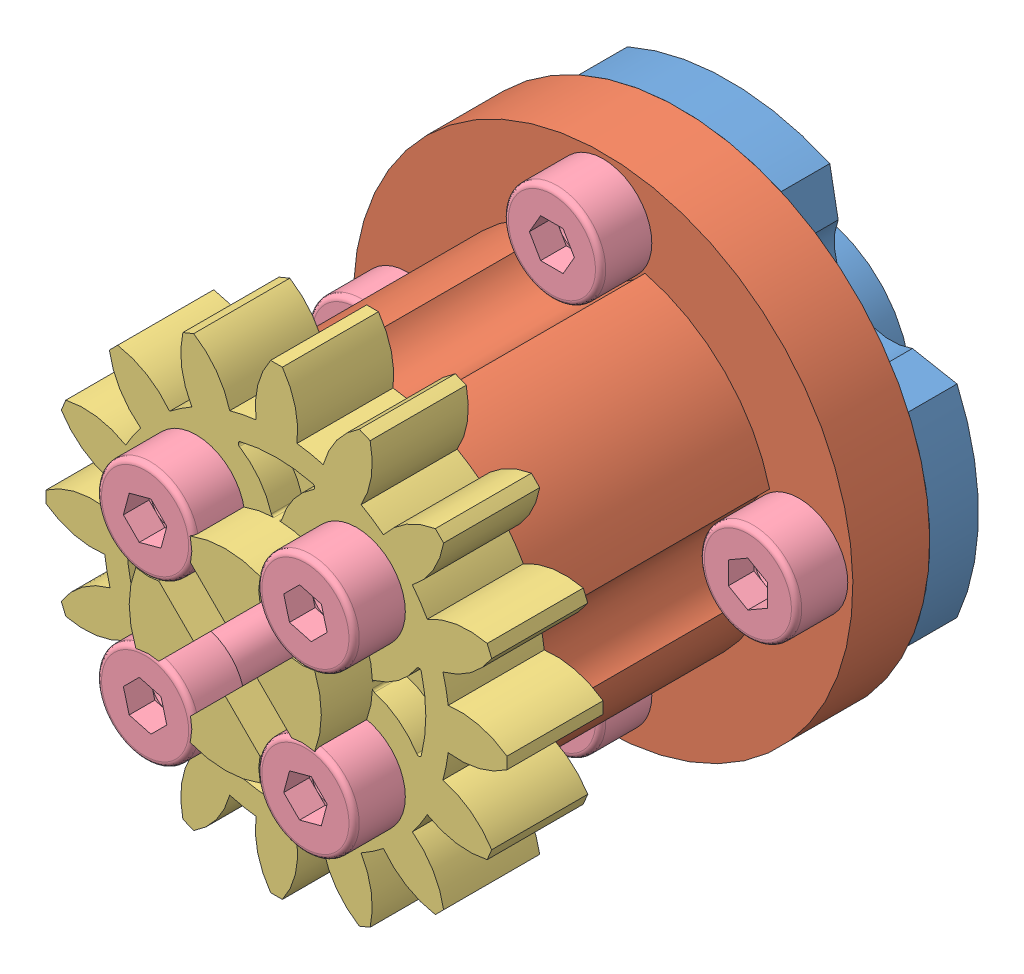
SolidWorks assembly Adapter-Servo-Zahnrad-16Z, configuration Standard. Lengths in mm.
Overall size (27.58 27.58 22.65).
11 component instances, 4 part files, 15 mates.
Components (placement in the parent):
- Servo-Horn-4er-modifiziert-1: Servo-Horn-4er-modifiziert [Standard] at origin size (19.5 19.5 5.7)
- Adapter-Servo-Zahnrad-16Z-1: Adapter-Servo-Zahnrad-16Z [Standard] at (0 0 4.8) x (-0.707107 0.707107 0) z (0 0 1) size (19.5 19.5 12)
- Lego Zahnrad 16Z-1: Lego Zahnrad 16Z [Standard] at (0 0 15.675) x (-0.707107 0.707107 0) z (0 0 1) size (18 18 7.75)
- DIN 912 M2 x 6 --- 6N-1: DIN 912 M2 x 6 --- 6N [DIN 912 M2 x 6 --- 6N] at (-3.1289 -3.1289 19.55) x (0 0 -1) z (-0.707107 0.707107 0) size (8 3.8 3.8)
- DIN 912 M2 x 6 --- 6N-2: DIN 912 M2 x 6 --- 6N [DIN 912 M2 x 6 --- 6N] at (-3.1289 3.1289 19.55) x (0 0 -1) z (0.707107 0.707107 0) size (8 3.8 3.8)
- DIN 912 M2 x 6 --- 6N-3: DIN 912 M2 x 6 --- 6N [DIN 912 M2 x 6 --- 6N] at (3.1289 3.1289 19.55) x (0 0 -1) z (0.707107 -0.707107 0) size (8 3.8 3.8)
- DIN 912 M2 x 6 --- 6N-4: DIN 912 M2 x 6 --- 6N [DIN 912 M2 x 6 --- 6N] at (3.1289 -3.1289 19.55) x (0 0 -1) z (-0.707107 -0.707107 0) size (8 3.8 3.8)
- DIN 912 M2 x 6 --- 6N-5: DIN 912 M2 x 6 --- 6N [DIN 912 M2 x 6 --- 6N] at (0 7.65 6.8) x (0 0 -1) z (0 1 0) size (8 3.8 3.8)
- DIN 912 M2 x 6 --- 6N-6: DIN 912 M2 x 6 --- 6N [DIN 912 M2 x 6 --- 6N] at (7.65 0 6.8) x (0 0 -1) z (1 0 0) size (8 3.8 3.8)
- DIN 912 M2 x 6 --- 6N-7: DIN 912 M2 x 6 --- 6N [DIN 912 M2 x 6 --- 6N] at (0 -7.65 6.8) x (0 0 -1) z (0 -1 0) size (8 3.8 3.8)
- DIN 912 M2 x 6 --- 6N-8: DIN 912 M2 x 6 --- 6N [DIN 912 M2 x 6 --- 6N] at (-7.65 0 6.8) x (0 0 -1) z (-1 0 0) size (8 3.8 3.8)
Mates (geometry in assembly coordinates):
- Konzentrisch1: concentric aligned: cylinder of Adapter-Servo-Zahnrad-16Z-1 through (0 0 13.8) axis (0 0 -1) radius 3.75; cylinder of Lego Zahnrad 16Z-1 through (0 0 19.55) axis (0 0 -1) radius 3.75
- Deckungsgleich5: coincident anti-aligned: plane of Adapter-Servo-Zahnrad-16Z-1 through (0 0 13.8) normal (0 0 1); plane of Lego Zahnrad 16Z-1 through (16.9706 -4.2426 13.8) normal (0 0 -1)
- Parallel1: parallel aligned: plane of Adapter-Servo-Zahnrad-16Z-1; plane of Lego Zahnrad 16Z-1 through (0.6187 -0.6187 11.8) normal (-0.707107 0.707107 0)
- Konzentrisch2: concentric aligned: cylinder of Adapter-Servo-Zahnrad-16Z-1 through (-3.1289 -3.1289 13.8) axis (0 0 1) radius 0.8; cylinder of DIN 912 M2 x 6 --- 6N-1 through (-3.1289 -3.1289 51.3) axis (0 0 1) radius 1
- Deckungsgleich7: coincident anti-aligned: plane of Lego Zahnrad 16Z-1 through (16.9706 -4.2426 17.55) normal (0 0 1); plane of DIN 912 M2 x 6 --- 6N-1 through (-4.4725 -4.4725 17.55) normal (0 0 -1)
- Deckungsgleich8: coincident aligned: plane of Adapter-Servo-Zahnrad-16Z-1; plane of DIN 912 M2 x 6 --- 6N-1 through (-3.1289 -3.1289 19.55) normal (-0.707107 0.707107 0)
- Deckungsgleich9: coincident aligned: plane of Servo-Horn-4er-modifiziert-1 through (0 0 0) normal (1 0 0); plane of assembly through (0 0 0) normal (1 0 0)
- Deckungsgleich10: coincident aligned: plane of Servo-Horn-4er-modifiziert-1 through (0 0 0) normal (0 0 1); plane of assembly through (0 0 0) normal (0 0 1)
- Deckungsgleich11: coincident aligned: plane of Servo-Horn-4er-modifiziert-1 through (0 0 0) normal (0 1 0); plane of assembly through (0 0 0) normal (0 1 0)
- Deckungsgleich12: coincident anti-aligned: plane of Servo-Horn-4er-modifiziert-1 through (0 4.5 1.8) normal (0 0 1); plane of Adapter-Servo-Zahnrad-16Z-1 through (0 0 1.8) normal (0 0 -1)
- Konzentrisch3: concentric aligned: cylinder of Servo-Horn-4er-modifiziert-1 through (0 0 0) axis (0 0 1) radius 4.1; cylinder of Adapter-Servo-Zahnrad-16Z-1 through (0 0 1.8) axis (0 0 1) radius 9.75
- Konzentrisch4: concentric aligned: cylinder of Servo-Horn-4er-modifiziert-1 through (0 7.65 -3.1) axis (0 0 1) radius 0.9; cylinder of Adapter-Servo-Zahnrad-16Z-1 through (0 7.65 1.8) axis (0 0 1) radius 1.05
- Konzentrisch5: concentric aligned: cylinder of Adapter-Servo-Zahnrad-16Z-1 through (0 7.65 1.8) axis (0 0 1) radius 1.05; cylinder of DIN 912 M2 x 6 --- 6N-5 through (0 7.65 38.55) axis (0 0 1) radius 1
- Deckungsgleich13: coincident anti-aligned: plane of Adapter-Servo-Zahnrad-16Z-1 through (0 0 4.8) normal (0 0 1); plane of DIN 912 M2 x 6 --- 6N-5 through (-1.9 7.65 4.8) normal (0 0 -1)
- Deckungsgleich14: coincident anti-aligned: plane of DIN 912 M2 x 6 --- 6N-5; plane of assembly through (0 0 0) normal (1 0 0)
